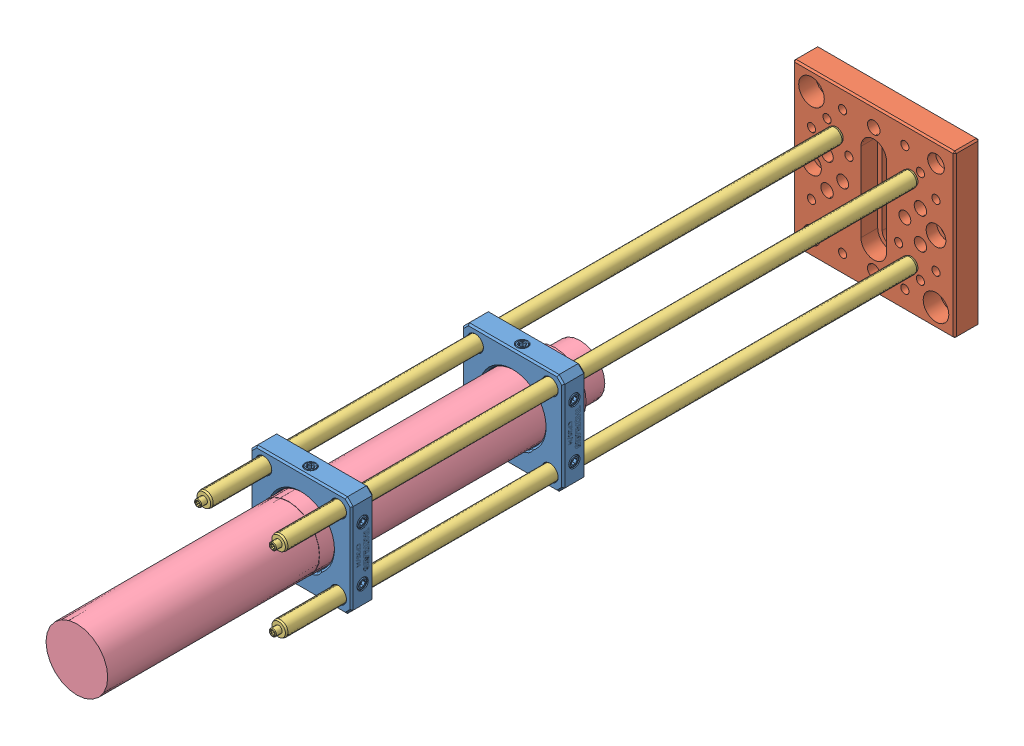
SolidWorks assembly Mag03Mount1V1, configuration Default. Lengths in mm.
Overall size (65 65 330).
8 component instances, 4 part files, 13 mates.
Components (placement in the parent):
- CP35_M-Step_Mag03Holder-1: CP35_M-Step_Mag03Holder [Default] at (-19.9986 3.5176 62.0754) size (40.87 40.64 8.89)
- CP35_M-Step_Mag03Holder-2: CP35_M-Step_Mag03Holder [Default] at (-19.9986 3.5176 -22.9246) size (40.87 40.64 8.89)
- UBP2_M-Solidworks-1: UBP2_M-Solidworks [Default] at (-52.4987 36.0176 -163.4796) x (-1 0 0) z (0 1 0) size (65 10 65)
- ER10-Solidworks-1: ER10-Solidworks [Default] at (-33.9327 17.3911 -38.9655) x (1 0 0) z (0 -1 0) size (5.99 259.08 5.99)
- ER10-Solidworks-2: ER10-Solidworks [Default] at (-3.9327 -12.6088 -38.9655) x (1 0 0) z (0 -1 0) size (5.99 259.08 5.99)
- ER10-Solidworks-3: ER10-Solidworks [Default] at (-3.9327 17.3911 -38.9655) x (1 0 0) z (0 -1 0) size (5.99 259.08 5.99)
- ER10-Solidworks-4: ER10-Solidworks [Default] at (-33.9327 -12.6088 -38.9655) x (1 0 0) z (0 -1 0) size (5.99 259.08 5.99)
- Mag03_Bartington-2: Mag03_Bartington [Default] at (-19.9986 3.5176 -35.4796) x (1 0 0) z (0 -1 0) size (25 202 25)
Mates (geometry in assembly coordinates):
- Concentric1: concentric aligned: cylinder of CP35_M-Step_Mag03Holder-1 through (-19.9986 3.5176 58.9004) axis (0 0 1) radius 12.7762; cylinder of CP35_M-Step_Mag03Holder-2 through (-19.9986 3.5176 -26.0996) axis (0 0 1) radius 12.7762
- Distance3: distance = 85 mm aligned: plane of CP35_M-Step_Mag03Holder-2 through (-40.3186 -16.8024 -27.3696) normal (0 0 -1); plane of CP35_M-Step_Mag03Holder-1 through (-40.3186 -16.8024 57.6304) normal (0 0 -1)
- Concentric3: concentric aligned: cylinder of CP35_M-Step_Mag03Holder-2 through (-4.9987 18.5175 -27.3696) axis (0 0 1) radius 3.0099; cylinder of ER10-Solidworks-3 through (-4.9987 18.5175 71.6304) axis (0 0 1) radius 2.9972
- Concentric4: concentric aligned: cylinder of CP35_M-Step_Mag03Holder-2 through (-34.9986 18.5175 -27.3696) axis (0 0 1) radius 3.0099; cylinder of ER10-Solidworks-1 through (-34.9986 18.5175 71.6304) axis (0 0 1) radius 2.9972
- Concentric5: concentric aligned: cylinder of CP35_M-Step_Mag03Holder-1 through (-4.9987 -11.4824 57.6304) axis (0 0 1) radius 3.0099; cylinder of ER10-Solidworks-2 through (-4.9987 -11.4824 71.6304) axis (0 0 1) radius 2.9972
- Concentric6: concentric aligned: cylinder of CP35_M-Step_Mag03Holder-1 through (-34.9986 -11.4824 57.6304) axis (0 0 1) radius 3.0099; cylinder of ER10-Solidworks-4 through (-34.9986 -11.4824 71.6304) axis (0 0 1) radius 2.9972
- Coincident1: coincident anti-aligned: plane of UBP2_M-Solidworks-1 through (12.5013 -28.9824 -182.3696) normal (0 0 1); plane of ER10-Solidworks-4 through (-32.2554 -11.4824 -182.3696) normal (0 0 -1)
- Coincident2: coincident anti-aligned: plane of UBP2_M-Solidworks-1 through (12.5013 -28.9824 -182.3696) normal (0 0 1); plane of ER10-Solidworks-1 through (-32.2554 18.5175 -182.3696) normal (0 0 -1)
- Coincident3: coincident anti-aligned: plane of UBP2_M-Solidworks-1 through (12.5013 -28.9824 -182.3696) normal (0 0 1); plane of ER10-Solidworks-3 through (-2.2555 18.5175 -182.3696) normal (0 0 -1)
- Coincident4: coincident anti-aligned: plane of UBP2_M-Solidworks-1 through (12.5013 -28.9824 -182.3696) normal (0 0 1); plane of ER10-Solidworks-2 through (-2.2555 -11.4824 -182.3696) normal (0 0 -1)
- Concentric7: concentric anti-aligned: cylinder of CP35_M-Step_Mag03Holder-2 through (-19.9986 3.5176 -26.0996) axis (0 0 1) radius 12.7762; cylinder of Mag03_Bartington-2 through (-19.9986 3.5176 52.6304) axis (0 0 -1) radius 12.5
- Distance4: distance = 320 mm aligned: plane of UBP2_M-Solidworks-1 through (12.5013 -28.9824 -163.4796) normal (0 0 1); plane of Mag03_Bartington-2 through (-19.9986 3.5176 156.5204) normal (0 0 1)
- Distance5: distance = 90 mm aligned: plane of Mag03_Bartington-2 through (-19.9986 3.5176 156.5204) normal (0 0 1); plane of CP35_M-Step_Mag03Holder-1 through (-40.3186 -16.8024 66.5204) normal (0 0 1)
